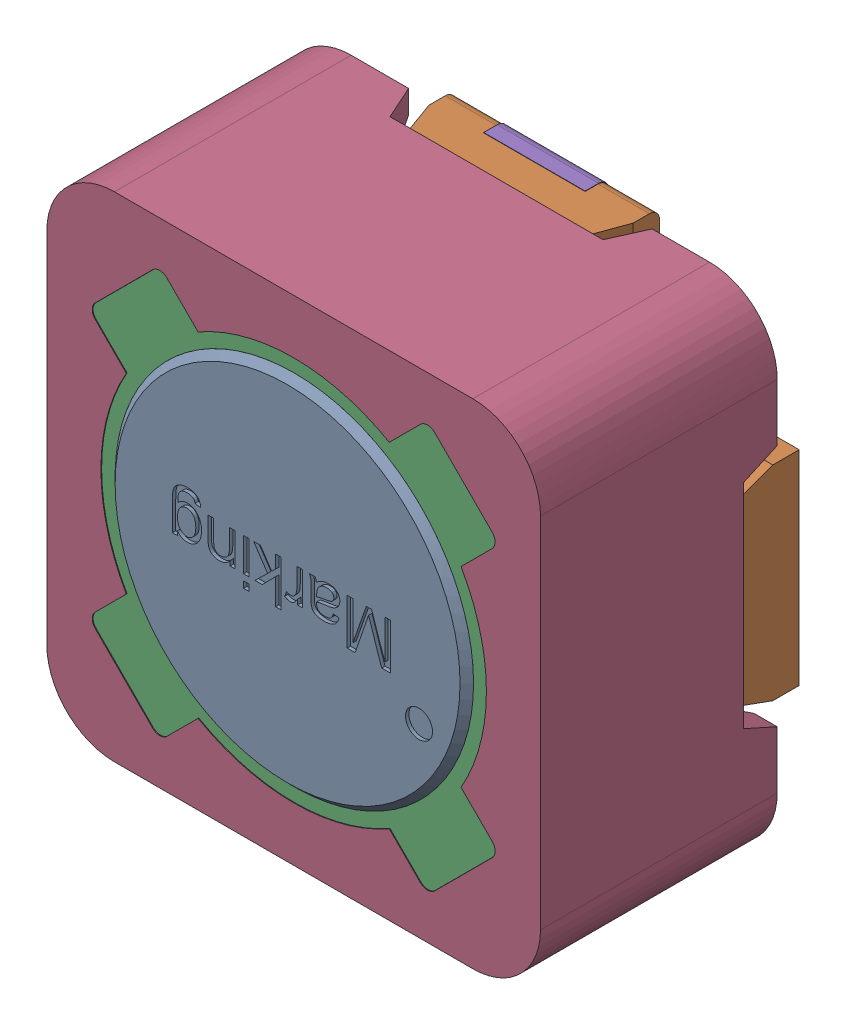
SolidWorks assembly L2, configuration Default. Lengths in mm.
Overall size (7.3 7.3 4).
12 component instances, 7 part files, 0 mates.
Components (placement in the parent):
- IndPDA_7345-1: IndPDA_7345 [Default] at (38.1509 8.6107 0.3) size (7.3 7.3 4)
  - Ferrite_5.3x3.6-1: Ferrite_5.3x3.6 [Default] at (0 0 0.15) size (5.3 5.3 3.6)
  - Umspritzung_1-1: Umspritzung_1 [Default] at (0 0 0.66) x (1 0 0) z (0 0 -1) size (7.15 7.15 0.9)
  - Glue_2-1: Glue_2 [Default] at origin size (5.95 5.95 2.94)
  - Ferrite-Ring7.3x3.5x5.7-1: Ferrite-Ring7.3x3.5x5.7 [Default] at (0 0 0.16) size (7.3 7.3 3.5)
  - Leadframe-1: Leadframe [Default] at origin size (7.19 7.19 3.21)
    - Leadframe_3-1: Leadframe_3 [Default] at origin size (5.16 2.58 0.5)
    - Leadframe_4-1: Leadframe_4 [Default] at origin size (5.16 2.58 0.5)
    - contact-1: contact [Default] at (-2.3342 -2.3342 -3.3) x (0.5 -0.5 0.707107) z (0.707107 0.707107 0) size (2.16 2.16 0.93)
    - contact-2: contact [Default] at (2.3342 -2.3342 -3.3) x (0.5 0.5 0.707107) z (-0.707107 0.707107 0) size (2.16 2.16 0.93)
    - contact-3: contact [Default] at (2.3342 2.3342 -3.3) x (-0.5 0.5 0.707107) z (-0.707107 -0.707107 0) size (2.16 2.16 0.93)
    - contact-4: contact [Default] at (-2.3342 2.3342 -3.3) x (-0.5 -0.5 0.707107) z (0.707107 -0.707107 0) size (2.16 2.16 0.93)
